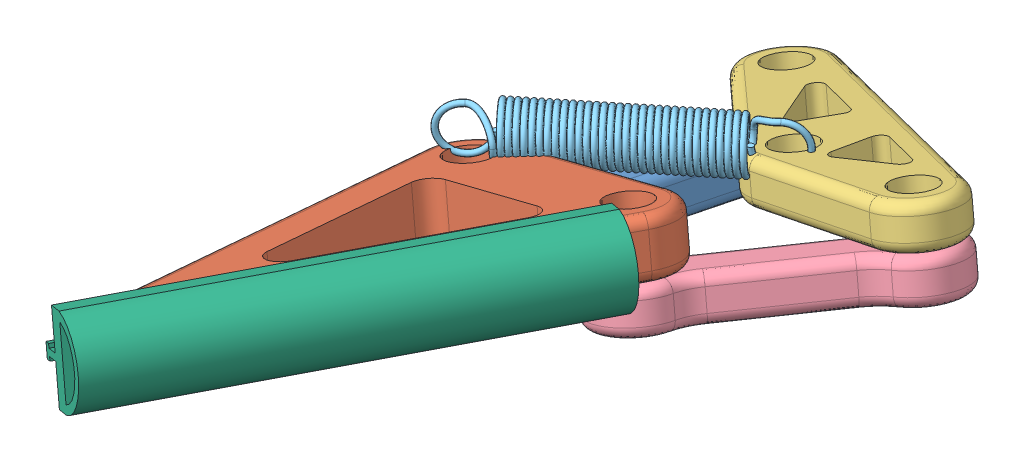
SolidWorks assembly Finger, configuration Default. Lengths in mm.
Overall size (67.3 44.6 128.41).
6 component instances, 6 part files, 10 mates.
Components (placement in the parent):
- 7.3mmLink-1: 7.3mmLink [Default] at (1.7597 112.3223 79.7725) x (0.080937 -0.137777 -0.987151) z (-0.963475 -0.264472 -0.042084) size (61.38 6.6 13.2)
- EndLink-3: EndLink [Default] at (-2.9163 106.3709 75.6986) x (-0.116128 -0.188547 -0.975174) z (0.959869 0.231037 -0.158976) size (76.63 8.38 40.37)
- TriLink1-5: TriLink1 [Default] at (27.3419 112.7045 61.8309) x (-0.957326 -0.271867 -0.098056) z (0.135503 -0.122541 -0.98317) size (60.28 6.6 30.89)
- 5mmLink-4: 5mmLink [Default] at (30.379 120.5143 83.1032) x (0.602782 0.032457 -0.797245) z (-0.755968 -0.296437 -0.583641) size (46.2 6.6 13.2)
- 9654K127_STEEL EXTENSION SPRING-1: 9654K127_STEEL EXTENSION SPRING [9654K127] at (11.6747 121.3707 71.4906) x (0.777146 0 -0.62932) z (0.62932 0 0.777146) size (44.45 7.99 8.44)
- SoftFinger-1: SoftFinger [Default] at (3.5306 127.6837 154.9742) x (-0.255276 0.954501 -0.15415) z (0.420777 -0.033869 -0.906532) size (12.7 10.74 68.58)
Mates (geometry in assembly coordinates):
- Coincident34: coincident aligned: cylinder of TriLink1-5 through (46.6088 126.1326 59.2278) axis (0.255276 -0.954501 0.15415) radius 3.3; circle of 5mmLink-4
- Coincident46: coincident anti-aligned: plane of TriLink1-5 through (48.2936 119.8329 60.2452) normal (0.255276 -0.954501 0.15415); plane of 5mmLink-4 through (41.148 122.1909 86.6789) normal (-0.255276 0.954501 -0.15415)
- Coincident51: coincident anti-aligned: plane of 7.3mmLink-1 through (12.677 113.2806 78.6546) normal (-0.255276 0.954501 -0.15415); plane of EndLink-3 through (28.4018 118.7618 86.5543) normal (0.255276 -0.954501 0.15415)
- Concentric34: concentric anti-aligned: cylinder of 7.3mmLink-1 through (3.4058 105.2046 86.8169) axis (-0.255276 0.954501 -0.15415) radius 3.3; cylinder of EndLink-3 through (-0.4188 119.5049 84.5074) axis (0.255276 -0.954501 0.15415) radius 3.3
- Concentric35: concentric anti-aligned: cylinder of EndLink-3 through (26.2621 126.7625 85.2622) axis (0.255276 -0.954501 0.15415) radius 3.3; cylinder of 5mmLink-4 through (30.0866 112.4621 87.5717) axis (-0.255276 0.954501 -0.15415) radius 3.3
- Coincident52: coincident anti-aligned: plane of EndLink-3 through (28.4018 118.7618 86.5543) normal (0.255276 -0.954501 0.15415); plane of 5mmLink-4 through (41.148 122.1909 86.6789) normal (-0.255276 0.954501 -0.15415)
- Concentric30: concentric anti-aligned: cylinder of 7.3mmLink-1 through (7.3053 98.5665 39.256) axis (-0.255276 0.954501 -0.15415) radius 3.3; cylinder of TriLink1-5 through (3.9357 111.1659 37.2212) axis (0.255276 -0.954501 0.15415) radius 3.3
- Coincident62: coincident anti-aligned: plane of EndLink-3 through (10.8457 130.4212 133.4472) normal (0.870506 0.296279 0.392986); plane of SoftFinger-1 through (32.8935 118.9204 93.2797) normal (-0.870506 -0.296279 -0.392986)
- Coincident63: coincident anti-aligned: plane of EndLink-3 through (11.3153 126.3644 130.6179) normal (0.255276 -0.954501 0.15415); plane of SoftFinger-1 through (11.1495 126.3079 130.543) normal (-0.255276 0.954501 -0.15415)
- Coincident64: coincident: line of EndLink-3 through (1.8061 129.5831 154.1027) axis (0.255276 -0.954501 0.15415); plane of SoftFinger-1 through (3.5306 127.6837 154.9742) normal (-0.420777 0.033869 0.906532)
